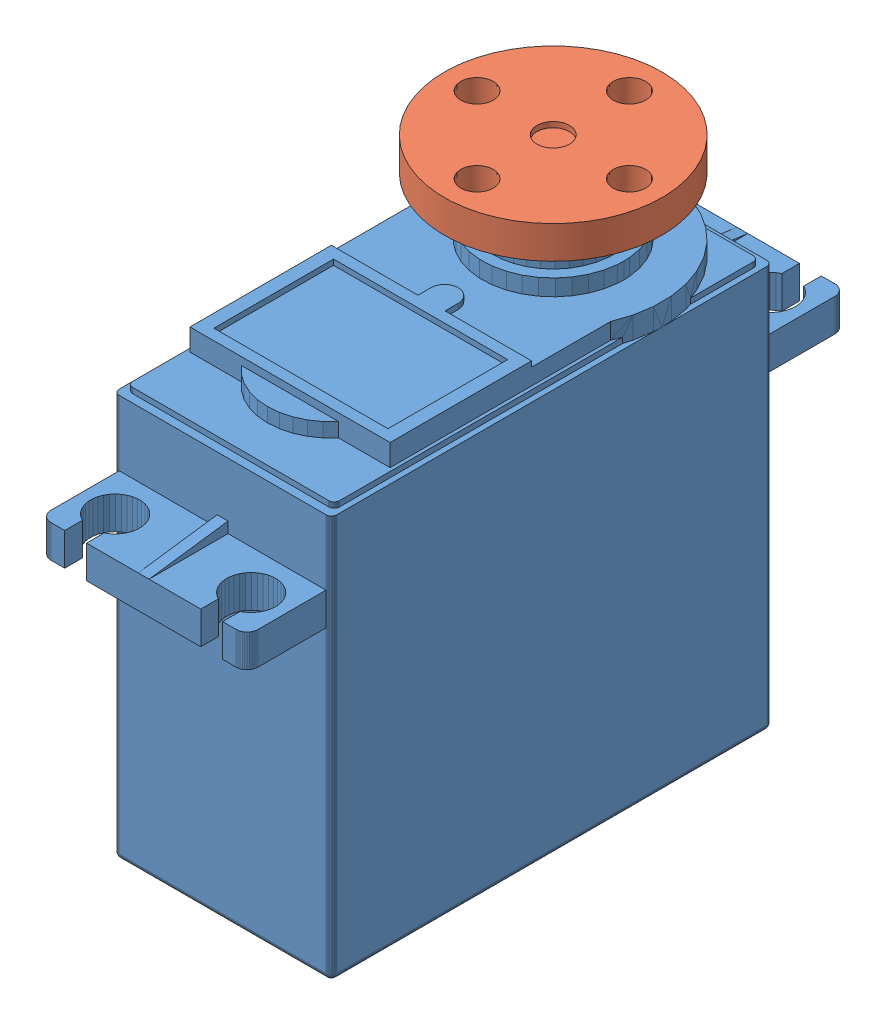
SolidWorks assembly Servo_and_metal_horn_edited v3 v1, configuration Default. Lengths in mm.
Overall size (20 47.3 55.02).
4 component instances, 2 part files, 0 mates.
Components (placement in the parent):
- Servo and metal horn v1-1: Servo and metal horn v1 [Default] at origin size (20 47.3 55.02)
  - servo v7-1: servo v7 [Default] at (0 -3 -26) size (20 46.8 55.02)
    - Component3-1: Component3 [Default] at origin size (20 46.8 55.02)
  - servo metal horn-1: servo metal horn [Default] at (0.0023 47.1264 -67.7367) x (1 0 0) z (0 0 -1) size (20 4.5 20)
